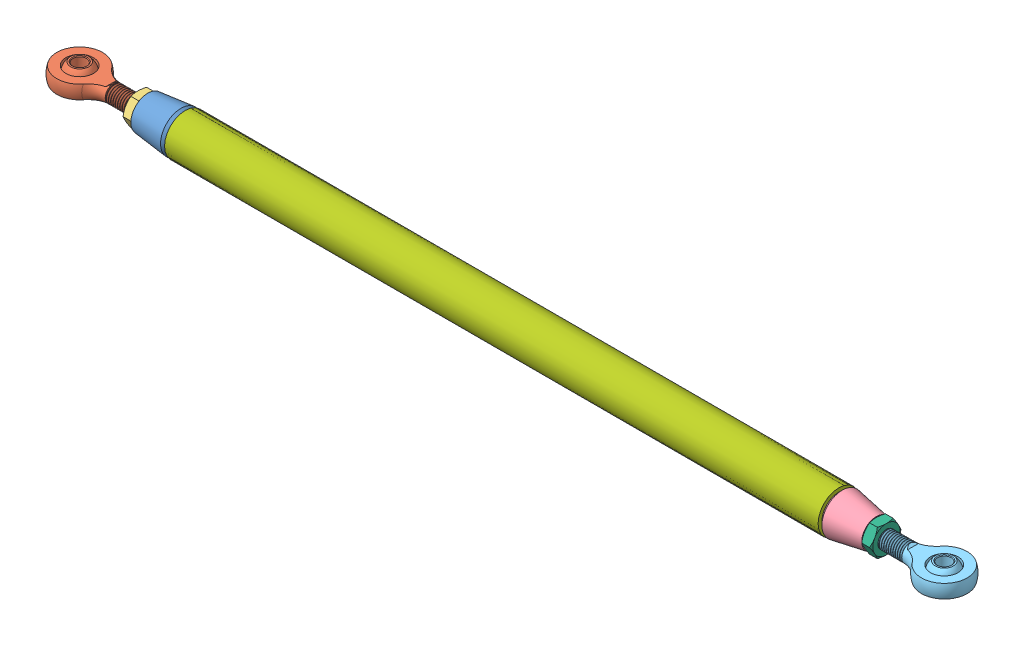
SolidWorks assembly Assem1, configuration Default. Lengths in mm.
Overall size (425.45 19.3 22.22).
9 component instances, 7 part files, 5 mates.
Components (placement in the parent):
- FS2-SU-A-0002-L, LEFT HAND ROD END TUBE END ASSEMBLY-1: FS2-SU-A-0002-L, LEFT HAND ROD END TUBE END ASSEMBLY [Default] at (-10.913 37.91 93.9213) size (77.79 19.05 22.23)
  - TUBE-END WELD NUT, Left Hand 0.3125-24 0.75 TUBE 0.065 WALL, 94640A114, MMC-1: TUBE-END WELD NUT, Left Hand 0.3125-24 0.75 TUBE 0.065 WALL, 94640A114, MMC [94640A114] x (0 1 0) z (0 0 1) size (19.05 35.46 19.05)
  - ROD END, STEEL BALL JOINT ID 0.25 0.3125-24 Left-Hand, 60645K821, MMC-1: ROD END, STEEL BALL JOINT ID 0.25 0.3125-24 Left-Hand, 60645K821, MMC [60645K821] at (-33.3375 0 0) x (0 0 -1) z (0 1 0) size (22.23 58.96 9.53)
  - THIN HEX NUT, Left Hand 0.3125-24 GRADE 5 STEEL , 99612A112, MMC-1: THIN HEX NUT, Left Hand 0.3125-24 GRADE 5 STEEL , 99612A112, MMC [99612A112] at (-19.8438 0 0) x (0 -1 0) z (0 0 1) size (12.7 5.58 14.66)
- FS2-SU-A-0002-R, RIGHT HAND ROD END TUBE END ASSEMBLY-1: FS2-SU-A-0002-R, RIGHT HAND ROD END TUBE END ASSEMBLY [Default] at (293.887 37.91 93.9213) x (-1 0 0) z (0 0 -1) size (77.79 19.05 22.23)
  - TUBE-END WELD NUT, Right Hand 0.3125-24 0.75 TUBE 0.065 WALL, 94640A110, MMC-1: TUBE-END WELD NUT, Right Hand 0.3125-24 0.75 TUBE 0.065 WALL, 94640A110, MMC [94640A110] x (0 1 0) z (0 0 1) size (19.05 35.46 19.05)
  - ROD END, STEEL BALL JOINT ID 0.25 0.3125-24 Right-Hand, 60645K822, MMC-1: ROD END, STEEL BALL JOINT ID 0.25 0.3125-24 Right-Hand, 60645K822, MMC [60645K822] at (-33.3375 0 0) x (0 0 -1) z (0 1 0) size (22.23 58.96 9.53)
  - THIN HEX NUT, 0.3125-24 GRADE 5 STEEL , 94846A510, MMC-1: THIN HEX NUT, 0.3125-24 GRADE 5 STEEL , 94846A510, MMC [94846A510] at (-19.8438 0 0) x (0 -1 0) z (0 0 1) size (12.7 5.58 14.66)
- FS2-SU-FS-ST-P-0001-V1, FS TIE ROD TUBE-1: FS2-SU-FS-ST-P-0001-V1, FS TIE ROD TUBE [Default] at (-10.913 37.91 93.9213) size (304.8 19.3 19.3)
Mates (geometry in assembly coordinates):
- Concentric7: concentric aligned: circle of FS2-SU-A-0002-L, LEFT HAND ROD END TUBE END ASSEMBLY-1/TUBE-END WELD NUT, Left Hand 0.3125-24 0.75 TUBE 0.065 WALL, 94640A114, MMC-1; circle of FS2-SU-FS-ST-P-0001-V1, FS TIE ROD TUBE-1
- Coincident2: coincident aligned: plane of FS2-SU-A-0002-L, LEFT HAND ROD END TUBE END ASSEMBLY-1/TUBE-END WELD NUT, Left Hand 0.3125-24 0.75 TUBE 0.065 WALL, 94640A114, MMC-1; plane of FS2-SU-FS-ST-P-0001-V1, FS TIE ROD TUBE-1 through (-10.913 45.784 93.9213) normal (-1 0 0)
- Concentric9: concentric anti-aligned: circle of FS2-SU-A-0002-R, RIGHT HAND ROD END TUBE END ASSEMBLY-1/TUBE-END WELD NUT, Right Hand 0.3125-24 0.75 TUBE 0.065 WALL, 94640A110, MMC-1; circle of FS2-SU-FS-ST-P-0001-V1, FS TIE ROD TUBE-1
- Coincident3: coincident aligned: circle of FS2-SU-A-0002-R, RIGHT HAND ROD END TUBE END ASSEMBLY-1/TUBE-END WELD NUT, Right Hand 0.3125-24 0.75 TUBE 0.065 WALL, 94640A110, MMC-1; plane of FS2-SU-FS-ST-P-0001-V1, FS TIE ROD TUBE-1 through (293.887 45.784 93.9213) normal (1 0 0)
- Parallel2: parallel aligned: plane of FS2-SU-A-0002-L, LEFT HAND ROD END TUBE END ASSEMBLY-1/ROD END, STEEL BALL JOINT ID 0.25 0.3125-24 Left-Hand, 60645K821, MMC-1 through (-71.238 41.085 105.0338) normal (0 1 0); plane of FS2-SU-A-0002-R, RIGHT HAND ROD END TUBE END ASSEMBLY-1/ROD END, STEEL BALL JOINT ID 0.25 0.3125-24 Right-Hand, 60645K822, MMC-1 through (354.212 41.085 82.8088) normal (0 1 0)
